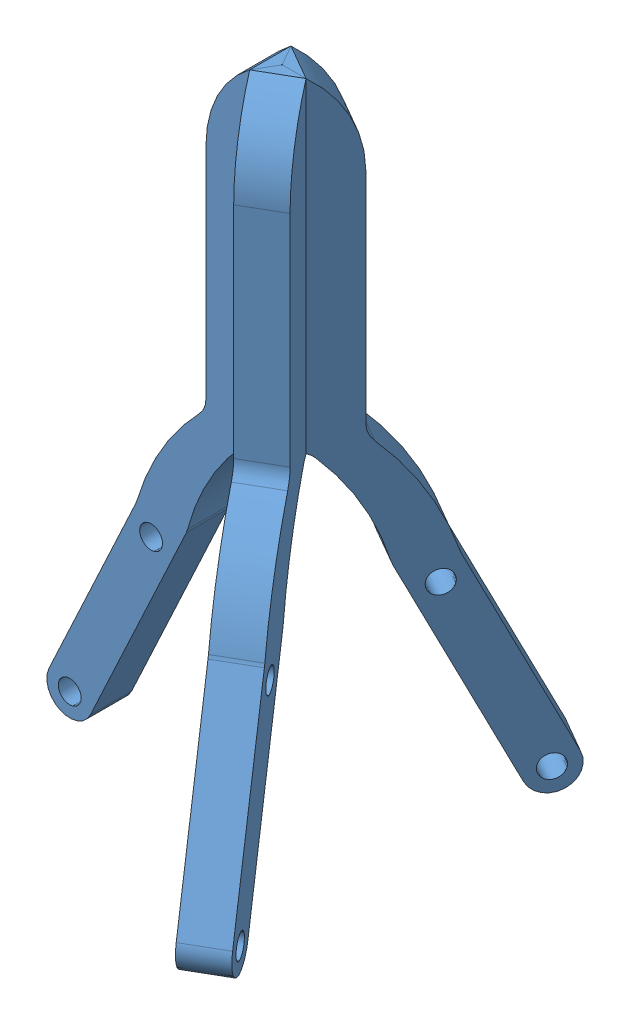
SolidWorks assembly Assem1, configuration Default. Lengths in mm.
Overall size (74.17 142.04 85.64).
3 component instances, 1 part files, 6 mates.
Components (placement in the parent):
- Talon V2-1: Talon V2 [Default] at (18.5209 70.2691 129.847) size (46.77 142.04 9)
- Talon V2-2: Talon V2 [Default] at (38.9982 70.2691 150.6696) x (-0.5 0 -0.866025) z (0.866025 0 -0.5) size (46.77 142.04 9)
- Talon V2-3: Talon V2 [Default] at (46.7925 70.2691 122.5244) x (-0.5 0 0.866025) z (-0.866025 0 -0.5) size (46.77 142.04 9)
Mates (geometry in assembly coordinates):
- Coincident1: coincident: plane of Talon V2-1 through (34.7705 93.8724 134.347) normal (0.866025 0 0.5); plane of Talon V2-2 through (35.6786 93.8724 132.7741) normal (-0.866025 0 -0.5)
- Coincident2: coincident: plane of Talon V2-1 through (18.5209 164.2408 129.847) normal (0 1 0); plane of Talon V2-2 through (42.5044 164.2408 144.5967) normal (0 1 0)
- Coincident3: coincident aligned: line of Talon V2-1 through (32.1724 164.2408 138.847) axis (0 -1 0); line of Talon V2-2 through (32.1724 164.2408 138.847) axis (0 -1 0)
- Coincident4: coincident: plane of Talon V2-1 through (18.5209 164.2408 129.847) normal (0 1 0); plane of Talon V2-3 through (46.7925 164.2408 122.5244) normal (0 1 0)
- Coincident5: coincident: line of Talon V2-2 through (39.9667 164.2408 134.347) axis (0 -1 0); line of Talon V2-3 through (39.9667 164.2408 134.347) axis (0 -1 0)
- Coincident6: coincident anti-aligned: plane of Talon V2-1 through (32.1724 93.8724 129.847) normal (0.866025 0 -0.5); plane of Talon V2-3 through (34.7705 93.8724 134.347) normal (-0.866025 0 0.5)
